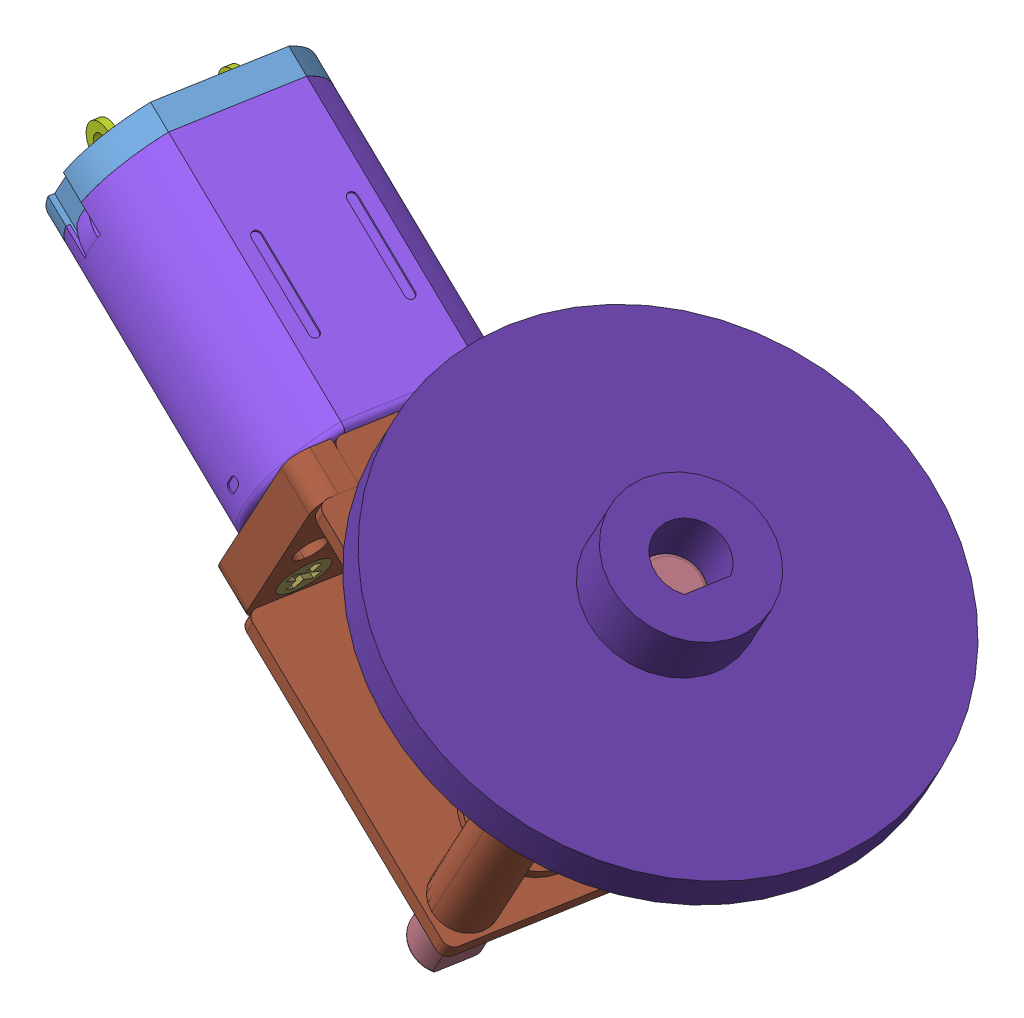
SolidWorks assembly Assem1, configuration Default. Lengths in mm.
Overall size (53.29 43.69 28.79).
24 component instances, 17 part files, 2 mates.
Components (placement in the parent):
- GM12-N20-双出轴-Motor.STEP-1: GM12-N20-双出轴-Motor.STEP [Default] at (28.4768 12.3654 49.5317) x (-0.173648 0 0.984808) z (-0.506459 -0.857627 -0.089303) size (12.48 35.2 30.02)
  - M057-8Y01A.STEP-1: M057-8Y01A.STEP [Default] at (-11.9731 34.4 -0.0079) x (1 0 -0.000001) z (-0.000001 0 -1) size (12.48 22.8 10.12)
    - ____________.STEP-1: ____________.STEP [Default] at origin size (11.83 5.2 10)
    - ____.STEP-1: ____.STEP [Default] at (0 13.2 0) x (-0.943879 0 0.330293) z (-0.330293 0 -0.943879) size (8 8.5 7.86)
    - ______.STEP-1: ______.STEP [Default] at (0 5 0) x (0.76218 0 0.647365) z (-0.647365 0 0.76218) size (6.5 3.16 6.5)
    - ____-0.STEP-1: ____-0.STEP [Default] at (0 1.5101 0) size (6.44 2.02 7.33)
    - __________.STEP-1: __________.STEP [Default] at (0 5.7 0) x (-0.943879 0 0.330293) z (-0.330293 0 -0.943879) size (1.99 3 1.8)
    - ____-1.STEP-1: ____-1.STEP [Default] at (0 5.7 0) x (0.999997 0 -0.002497) z (0.002497 0 0.999997) size (11.55 8.5 9.62)
    - ____-2.STEP-1: ____-2.STEP [Default] at (-3.1 2.45 0) x (-1 0 0) z (0 0 1) size (0.4 4.25 2)
    - ____-2.STEP-2: ____-2.STEP [Default] at (3.1 2.45 0) x (1 0 0) z (0 0 -1) size (0.4 4.25 2)
    - ________.STEP-1: ________.STEP [Default] at (-0.0269 14.9 -0.0079) x (1 0 0) z (0 0 1) size (12.48 14.42 10.05)
    - __.STEP-1: __.STEP [Default] at (0 18 0) x (-0.799859 0 0.600187) z (0.600187 0 0.799859) size (1 21.6 1)
    - ________-3.STEP-1: ________-3.STEP [Default] at (0 2.38 0) x (0.383204 0 -0.923664) z (0.923664 0 0.383204) size (1.8 0.14 1.8)
  - __________-4.STEP-1: __________-4.STEP [Default] at (-11.9731 17.6 -0.0079) x (-1 0 0) z (0 0 1) size (12 18 11)
  - ____________-5.STEP-1: ____________-5.STEP [Default] at (-8.1717 26.8 2.7915) x (0.891574 0 -0.452876) z (-0.452876 0 -0.891574) size (2.5 4 2.5)
  - ____________-5.STEP-2: ____________-5.STEP [Default] at (-15.7745 26.8 -2.8073) x (0.897232 0 0.441559) z (0.441559 0 -0.897232) size (2.5 4 2.5)
  - ____________-5.STEP-3: ____________-5.STEP [Default] at (-11.9731 17.9 4.9921) x (0.198842 0.980032 0) z (-0.980032 0.198842 0) size (2.5 4 2.5)
  - ____________-5.STEP-4: ____________-5.STEP [Default] at (-11.9731 17.9 -5.0079) x (0.99911 0.042183 0) z (0.042183 -0.99911 0) size (2.5 4 2.5)
  - Engrenagem reta28-D.STEP-1: Engrenagem reta28-D.STEP [Default] at (-11.9731 4.96 -1.2079) x (1 0 0) z (0 0 1) size (5.58 5.58 30.02)
  - Engrenagem reta22-11.STEP-1: Engrenagem reta22-11.STEP [Default] at (-11.9731 8.54 1.7421) x (-0.992642 0.12109 0) z (0 0 -1) size (3.59 3.6 3.7)
  - WHEEL.STEP-1: WHEEL.STEP [Default] at (-14.7231 13.8 17.2335) x (-0.11679 0.993157 0) z (-0.993157 -0.11679 0) size (3.87 7.9 3.87)
  - WORM.STEP-1: WORM.STEP [Default] at (-12.1256 -17.9199 -0.2314) x (0.999993 0 0.003797) z (-0.003797 0 0.999993) size (2.48 4.58 2.44)
  - Engrenagem reta22-11.STEP-2: Engrenagem reta22-11.STEP [Default] at (-13.546 10.6103 3.1144) x (-0.99128 0.131771 0) z (0 0 -1) size (3.59 3.6 3.7)
- hand_pulley_wheel1-1: hand_pulley_wheel1 [Default] at (32.6785 25.6045 38.1147) x (0.173648 0 -0.984808) z (0.844598 -0.514272 0.148925) size (25 5 25)
Mates (geometry in assembly coordinates):
- Distance1: distance = 0.1 mm: plane of hand_pulley_wheel-1 through (34.7894 26.6512 38.487) normal (-0.844598 0.514272 -0.148925); plane of GM12-N20-双出轴-Motor.STEP-1/Engrenagem reta28-D.STEP-1 through (33.4938 24.7088 37.1131) normal (0.844598 -0.514272 0.148925)
- Concentric4: concentric: cylinder of GM12-N20-双出轴-Motor.STEP-1/Engrenagem reta28-D.STEP-1 through (32.3469 25.0429 38.0563) axis (-0.50646 -0.857627 -0.089302) radius 1.5; cylinder of hand_pulley_wheel-1 through (33.6915 27.3198 38.2933) axis (-0.50646 -0.857627 -0.089302) radius 1.7
